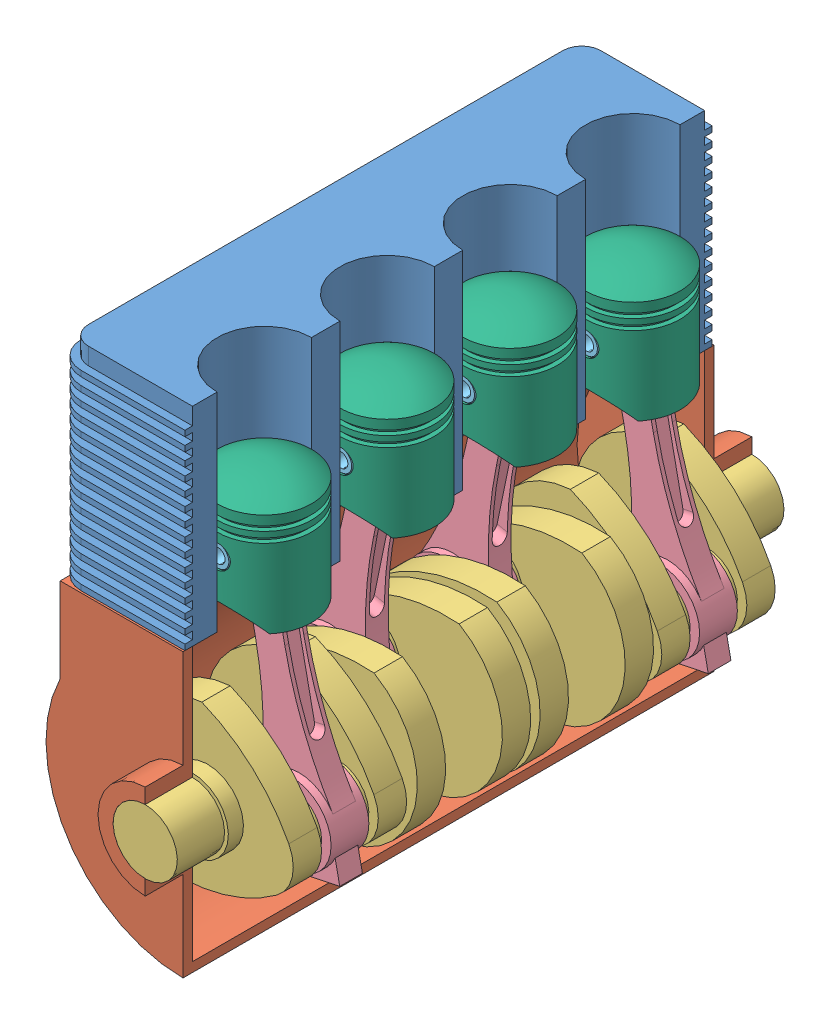
SolidWorks assembly final assembly, configuration Default. Lengths in mm.
Overall size (127.31 259.5 321).
15 component instances, 6 part files, 29 mates.
Components (placement in the parent):
- upper block-1: upper block [Default] at (93.6915 73.2018 476.9955) x (0 0 -1) z (1 0 0) size (279 110 69)
- lower block-1: lower block [Default] at (93.6915 -3.7982 481.9955) size (72.5 149.5 321)
- crank shaft-1: crank shaft [Default] at (93.6915 -3.7982 205.9955) x (0 0 1) z (0.227676 0.973737 0) size (321 92 88)
- connecting rod-1: connecting rod [Default] at (118.0349 -9.4901 438.9955) x (0.979207 0.202862 0) z (0 0 1) size (42 160.15 20)
- piston pin-1: piston pin [Default] at (93.6915 108.0148 438.9955) size (12.5 12.5 49)
- piston1-1: piston1 [Default] at (93.6915 77.5148 438.9955) size (50 64.17 50)
- piston1-3: piston1 [Default] at (93.6915 77.5148 243.9955) x (-1 0 0) z (0 0 -1) size (50 64.17 50)
- piston pin-3: piston pin [Default] at (93.6915 108.0148 243.9955) x (-0.173648 0.984808 0) z (0 0 -1) size (12.5 12.5 49)
- connecting rod-3: connecting rod [Default] at (118.0349 -9.4901 243.9955) x (-0.979207 -0.202862 0) z (0 0 -1) size (42 160.15 20)
- connecting rod-5: connecting rod [Default] at (69.3481 1.8938 373.9955) x (0.979207 -0.202862 0) z (0 0 1) size (42 160.15 20)
- piston1-5: piston1 [Default] at (93.6915 88.8986 373.9955) size (50 64.17 50)
- piston pin-5: piston pin [Default] at (93.6915 119.3986 373.9955) size (12.5 12.5 49)
- piston1-7: piston1 [Default] at (93.6915 88.8986 308.9955) x (-1 0 0) z (0 0 -1) size (50 64.17 50)
- piston pin-7: piston pin [Default] at (93.6915 119.3986 308.9955) x (-0.173648 0.984808 0) z (0 0 -1) size (12.5 12.5 49)
- connecting rod-7: connecting rod [Default] at (69.3481 1.8938 308.9955) x (-0.979207 0.202862 0) z (0 0 -1) size (42 160.15 20)
Mates (geometry in assembly coordinates):
- Coincident1: coincident: plane of upper block-1 through (93.6915 183.2018 476.9955) normal (1 0 0); plane of lower block-1 through (93.6915 21.2018 476.9955) normal (1 0 0)
- Coincident2: coincident: plane of upper block-1 through (38.6915 73.2018 466.9955) normal (0 -1 0); plane of lower block-1 through (93.6915 73.2018 476.9955) normal (0 1 0)
- Width1: width: plane of lower block-1 through (93.6915 -3.7982 481.9955) normal (0 0 1); plane of lower block-1 through (93.6915 -3.7982 200.9955) normal (0 0 -1); plane of upper block-1 through (93.6915 183.2018 476.9955) normal (0 0 1); plane of upper block-1 through (93.6915 183.2018 205.9955) normal (0 0 -1)
- Concentric1: concentric: cylinder of lower block-1 through (93.6915 -3.7982 476.9955) axis (0 0 1) radius 17; cylinder of crank shaft-1 through (93.6915 -3.7982 501.9955) axis (0 0 -1) radius 17
- Coincident3: coincident: plane of lower block-1 through (93.6915 -3.7982 501.9955) normal (0 0 1); plane of crank shaft-1 through (93.6915 -3.7982 501.9955) normal (0 0 1)
- Concentric2: concentric: cylinder of piston pin-1 through (93.6915 108.0148 463.4955) axis (0 0 -1) radius 6.25; cylinder of piston1-1 through (93.6915 108.0148 413.9955) axis (0 0 1) radius 6.25
- Width2: width: plane of piston1-1 through (93.6915 108.0148 426.9955) normal (0 0 1); plane of piston1-1 through (93.6915 108.0148 450.9955) normal (0 0 -1); plane of piston pin-1 through (93.6915 108.0148 414.4955) normal (0 0 -1); plane of piston pin-1 through (93.6915 108.0148 463.4955) normal (0 0 1)
- Concentric3: concentric: cylinder of connecting rod-1 through (93.6915 108.0148 448.9955) axis (0 0 -1) radius 6.25; cylinder of piston pin-1 through (93.6915 108.0148 463.4955) axis (0 0 -1) radius 6.25
- Width3: width: plane of piston1-1 through (93.6915 108.0148 426.9955) normal (0 0 1); plane of piston1-1 through (93.6915 108.0148 450.9955) normal (0 0 -1); plane of connecting rod-1 through (118.0349 -9.4901 448.9955) normal (0 0 1); plane of connecting rod-1 through (118.0349 -9.4901 428.9955) normal (0 0 -1)
- Concentric4: concentric: cylinder of crank shaft-1 through (118.0349 -9.4901 438.9955) axis (0 0 1) radius 16; cylinder of connecting rod-1 through (118.0349 -9.4901 448.9955) axis (0 0 -1) radius 16
- Concentric5: concentric: cylinder of upper block-1 through (93.6915 183.2018 438.9955) axis (0 -1 0) radius 25; cylinder of piston1-1 through (93.6915 140.0148 438.9955) axis (0 1 0) radius 25
- Concentric10: concentric: cylinder of piston1-3 through (93.6915 108.0148 268.9955) axis (0 0 -1) radius 6.25; cylinder of piston pin-3 through (93.6915 108.0148 219.4955) axis (0 0 1) radius 6.25
- Width6: width: plane of piston1-3 through (93.6915 108.0148 255.9955) normal (0 0 -1); plane of piston1-3 through (93.6915 108.0148 231.9955) normal (0 0 1); plane of piston pin-3 through (93.6915 108.0148 268.4955) normal (0 0 1); plane of piston pin-3 through (93.6915 108.0148 219.4955) normal (0 0 -1)
- Concentric11: concentric: cylinder of piston pin-3 through (93.6915 108.0148 219.4955) axis (0 0 1) radius 6.25; cylinder of connecting rod-3 through (93.6915 108.0148 233.9955) axis (0 0 1) radius 6.25
- Width7: width: plane of piston1-3 through (93.6915 108.0148 255.9955) normal (0 0 -1); plane of piston1-3 through (93.6915 108.0148 231.9955) normal (0 0 1); plane of connecting rod-3 through (118.0349 -9.4901 233.9955) normal (0 0 -1); plane of connecting rod-3 through (118.0349 -9.4901 253.9955) normal (0 0 1)
- Concentric12: concentric: cylinder of crank shaft-1 through (118.0349 -9.4901 243.9955) axis (0 0 -1) radius 16; cylinder of connecting rod-3 through (118.0349 -9.4901 233.9955) axis (0 0 1) radius 16
- Concentric13: concentric: cylinder of upper block-1 through (93.6915 183.2018 243.9955) axis (0 -1 0) radius 25; cylinder of piston1-3 through (93.6915 140.0148 243.9955) axis (0 1 0) radius 25
- Concentric16: concentric: cylinder of piston1-5 through (93.6915 119.3986 348.9955) axis (0 0 1) radius 6.25; cylinder of piston pin-5 through (93.6915 119.3986 398.4955) axis (0 0 -1) radius 6.25
- Width10: width: plane of piston1-5 through (93.6915 119.3986 361.9955) normal (0 0 1); plane of piston1-5 through (93.6915 119.3986 385.9955) normal (0 0 -1); plane of piston pin-5 through (93.6915 119.3986 349.4955) normal (0 0 -1); plane of piston pin-5 through (93.6915 119.3986 398.4955) normal (0 0 1)
- Concentric17: concentric: cylinder of connecting rod-5 through (93.6915 119.3986 383.9955) axis (0 0 -1) radius 6.25; cylinder of piston pin-5 through (93.6915 119.3986 398.4955) axis (0 0 -1) radius 6.25
- Width11: width: plane of connecting rod-5 through (69.3481 1.8938 383.9955) normal (0 0 1); plane of connecting rod-5 through (69.3481 1.8938 363.9955) normal (0 0 -1); plane of piston pin-5 through (93.6915 119.3986 398.4955) normal (0 0 1); plane of piston pin-5 through (93.6915 119.3986 349.4955) normal (0 0 -1)
- Concentric18: concentric: cylinder of crank shaft-1 through (69.3481 1.8938 358.9955) axis (0 0 1) radius 16; cylinder of connecting rod-5 through (69.3481 1.8938 383.9955) axis (0 0 -1) radius 16
- Concentric19: concentric: cylinder of upper block-1 through (93.6915 183.2018 373.9955) axis (0 -1 0) radius 25; cylinder of piston1-5 through (93.6915 151.3986 373.9955) axis (0 1 0) radius 25
- Concentric23: concentric: cylinder of piston1-7 through (93.6915 119.3986 333.9955) axis (0 0 -1) radius 6.25; cylinder of piston pin-7 through (93.6915 119.3986 284.4955) axis (0 0 1) radius 6.25
- Width14: width: plane of piston1-7 through (93.6915 119.3986 320.9955) normal (0 0 -1); plane of piston1-7 through (93.6915 119.3986 296.9955) normal (0 0 1); plane of piston pin-7 through (93.6915 119.3986 333.4955) normal (0 0 1); plane of piston pin-7 through (93.6915 119.3986 284.4955) normal (0 0 -1)
- Concentric24: concentric: cylinder of piston pin-7 through (93.6915 119.3986 284.4955) axis (0 0 1) radius 6.25; cylinder of connecting rod-7 through (93.6915 119.3986 298.9955) axis (0 0 1) radius 6.25
- Width15: width: plane of connecting rod-7 through (69.3481 1.8938 298.9955) normal (0 0 -1); plane of connecting rod-7 through (69.3481 1.8938 318.9955) normal (0 0 1); plane of piston pin-7 through (93.6915 119.3986 284.4955) normal (0 0 -1); plane of piston pin-7 through (93.6915 119.3986 333.4955) normal (0 0 1)
- Concentric25: concentric: cylinder of crank shaft-1 through (69.3481 1.8938 323.9955) axis (0 0 -1) radius 16; cylinder of connecting rod-7 through (69.3481 1.8938 298.9955) axis (0 0 1) radius 16
- Concentric26: concentric: cylinder of upper block-1 through (93.6915 183.2018 308.9955) axis (0 -1 0) radius 25; cylinder of piston1-7 through (93.6915 151.3986 308.9955) axis (0 1 0) radius 25
